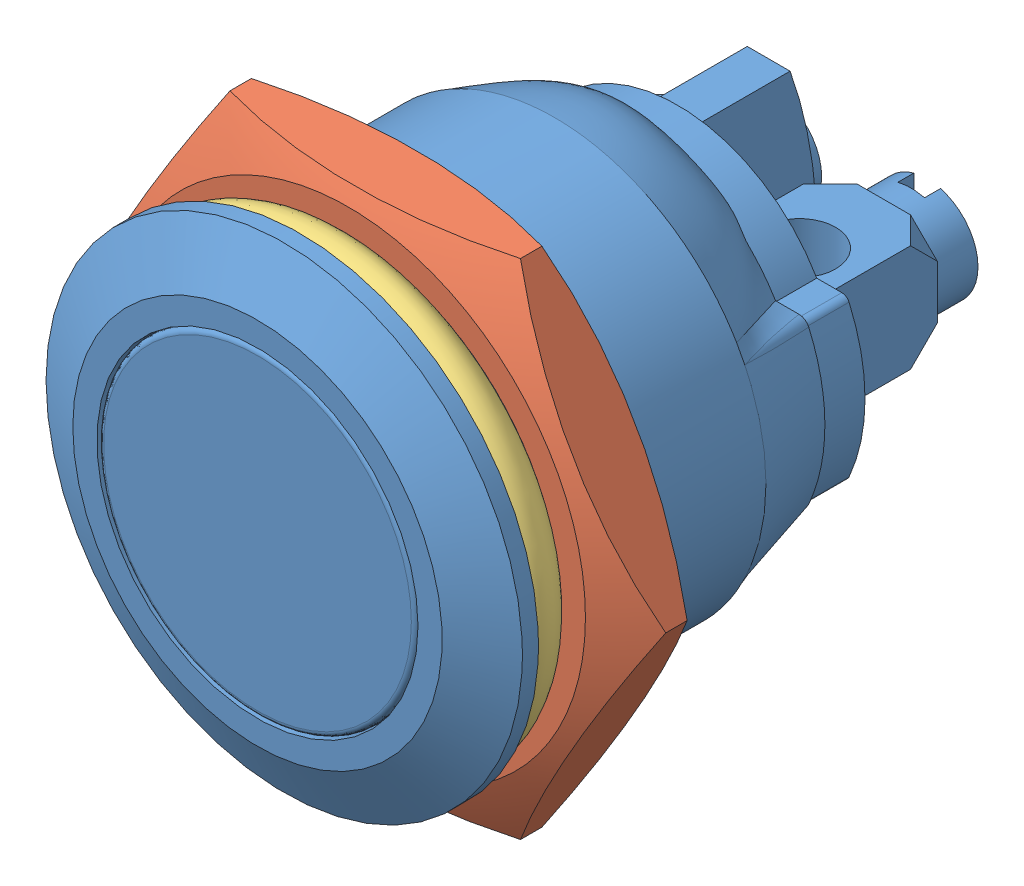
SolidWorks assembly button-with-ring, configuration Défaut. Lengths in mm.
Overall size (21.74 21.74 22.1).
3 component instances, 3 part files, 4 mates.
Components (placement in the parent):
- button-1: button [Défaut] at (-16.6108 4.4617 22.1) size (17.8 17.8 22.1)
- button-nut-1: button-nut [Défaut] at (-16.6108 4.4617 18.9) size (21.71 18.8 2.8)
- button-ring-2: button-ring [Défaut] at (-16.6108 4.4617 21.2) x (0.941391 0.337318 0) z (0 0 1) size (17 17 1.8)
Mates (geometry in assembly coordinates):
- Coaxiale1: concentric aligned: cylinder of button-1 through (-16.6108 4.4617 12.6) axis (0 0 1) radius 7.9; circle of button-ring-2
- Tangent3: tangent anti-aligned: plane of button-1 through (-16.6108 4.4617 22.1) normal (0 0 -1); torus of button-ring-2
- Coaxiale2: concentric anti-aligned: cylinder of button-1 through (-16.6108 4.4617 12.6) axis (0 0 1) radius 7.9; cylinder of button-nut-1 through (-16.6108 4.4617 20.3) axis (0 0 -1) radius 7.9
- Tangent4: tangent anti-aligned: plane of button-nut-1 through (-16.6108 4.4617 20.3) normal (0 0 1); torus of button-ring-2
